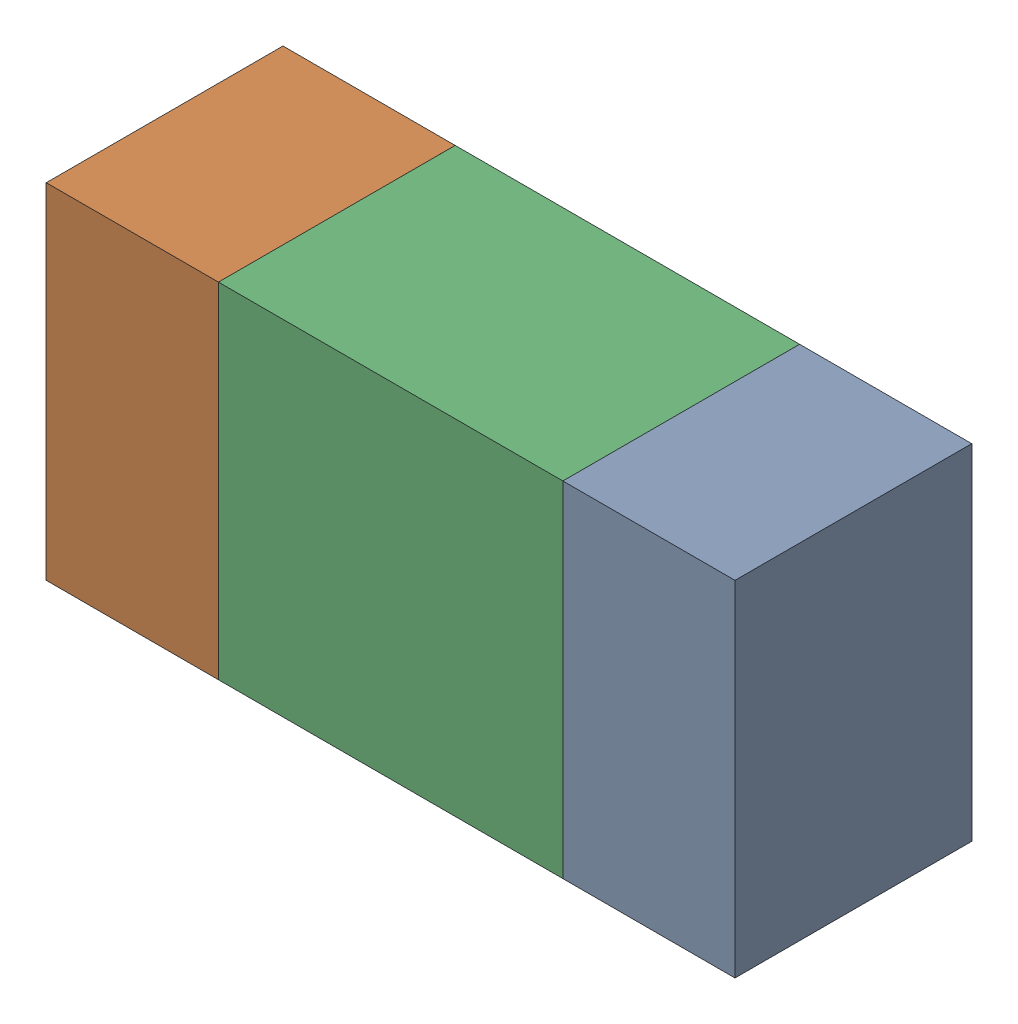
SolidWorks assembly R76, configuration ﾃﾞﾌｫﾙﾄ. Lengths in mm.
Overall size (1.6 0.8 0.55).
6 component instances, 2 part files, 0 mates.
Components (placement in the parent):
- 689261512-1: 689261512 [ﾃﾞﾌｫﾙﾄ] at (18.0999 56.2499 0) size (0.4 0.8 0.55)
  - Extruded_32-1: Extruded_32 [ﾃﾞﾌｫﾙﾄ] at origin size (0.4 0.8 0.55)
- 689261512-2: 689261512 [ﾃﾞﾌｫﾙﾄ] at (16.8999 56.2499 0) size (0.4 0.8 0.55)
  - Extruded_32-1: Extruded_32 [ﾃﾞﾌｫﾙﾄ] at origin size (0.4 0.8 0.55)
- 689261648-1: 689261648 [ﾃﾞﾌｫﾙﾄ] at (17.5 56.2499 0) size (0.8 0.8 0.55)
  - Extruded_33-1: Extruded_33 [ﾃﾞﾌｫﾙﾄ] at origin size (0.8 0.8 0.55)
